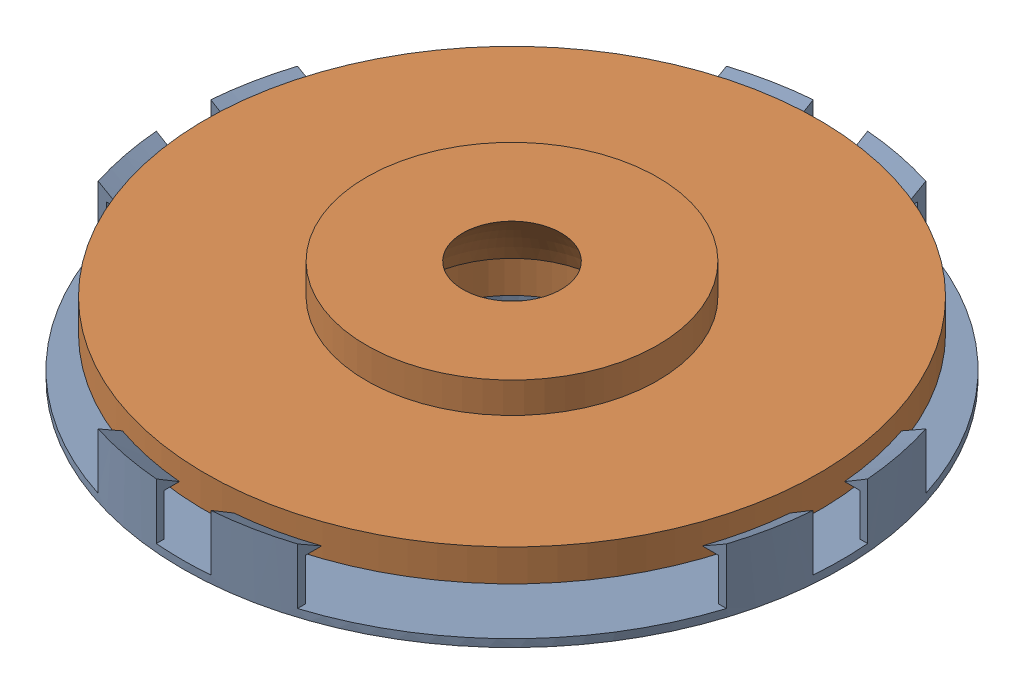
SolidWorks assembly СбЗеркало, configuration Default. Lengths in mm.
Overall size (110.64 13.26 110.64).
2 component instances, 2 part files, 2 mates.
Components (placement in the parent):
- ОправкаН-1: ОправкаН [По умолчанию] at origin size (86 8.3 86)
- Держатель-1: Держатель [По умолчанию] at (0 9.2555 0) x (-0.839141 0 -0.543913) z (-0.543913 0 0.839141) size (80 12.36 80)
Mates (geometry in assembly coordinates):
- Параллельность1: parallel anti-aligned: plane of ОправкаН-1 through (0 0.8 0) normal (0 1 0); plane of Держатель-1 through (-15.9437 5.0749 -10.3344) normal (0 -1 0)
- Концентричный1: concentric anti-aligned: circle of ОправкаН-1; circle of Держатель-1
